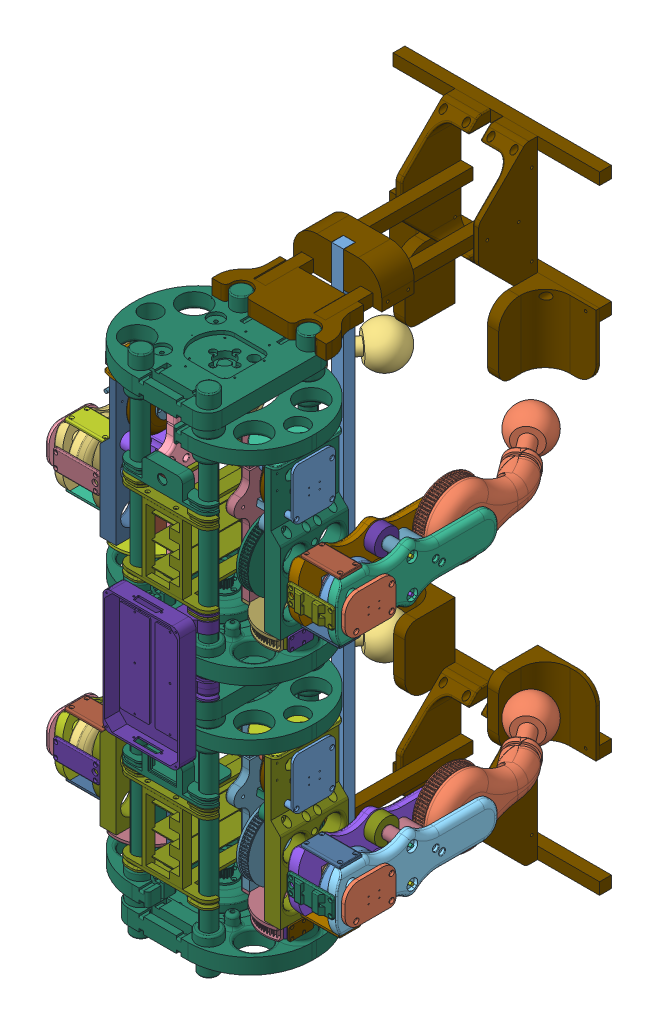
SolidWorks assembly openDogv2_12, configuration Default. Lengths in mm.
Overall size (507.74 1062 621.38).
170 component instances, 145 part files, 0 mates.
Components (placement in the parent):
- openDogv2_12.stp-1: openDogv2_12.stp [Default] at origin size (507.74 1062 621.38)
  - leg (1).stp-1: leg (1).stp [Default] at (0 150 0) size (214.22 298 498.86)
    - UpperLeg.stp-1: UpperLeg.stp [Default] at (-4.6931 5.6325 6.5458) size (199.22 129.38 296.86)
      - motor9225 v5 (2).stp-1: motor9225 v5 (2).stp [Default] at (-4 -156.5615 -13.5322) x (1 0 0) z (0 0.866025 0.5) size (39 92 92)
      - AMS.stp-1: AMS.stp [Default] at (-75 -241.6619 77.1108) x (1 0 0) z (0 0.707107 0.707107) size (28.8 88.43 93.61)
      - UpperLeg-0.stp-1: UpperLeg-0.stp [Default] at origin size (19 40 40)
      - UpperLeg-1.stp-1: UpperLeg-1.stp [Default] at origin size (119.92 20 20)
      - UpperLeg-2.stp-1: UpperLeg-2.stp [Default] at origin size (17.12 104.6 278)
      - UpperLeg-3.stp-1: UpperLeg-3.stp [Default] at origin size (82.92 5.08 5.08)
      - UpperLeg-4.stp-1: UpperLeg-4.stp [Default] at origin size (82.92 5.08 5.08)
      - UpperLeg-5.stp-1: UpperLeg-5.stp [Default] at origin size (20.04 104.6 278)
      - UpperLeg-6.stp-1: UpperLeg-6.stp [Default] at origin size (64.92 5.17 37.57)
      - UpperLeg-7.stp-1: UpperLeg-7.stp [Default] at origin size (66.92 5.17 37.57)
      - UpperLeg-8.stp-1: UpperLeg-8.stp [Default] at origin size (4 37 37)
      - UpperLeg-9.stp-1: UpperLeg-9.stp [Default] at origin size (4 37 37)
      - UpperLeg-10.stp-1: UpperLeg-10.stp [Default] at origin size (50 76 69.55)
      - UpperLeg-11.stp-1: UpperLeg-11.stp [Default] at origin size (55 114 114)
      - UpperLeg-12.stp-1: UpperLeg-12.stp [Default] at origin size (78.92 34.88 10)
      - UpperLeg-13.stp-1: UpperLeg-13.stp [Default] at origin size (18 42 42)
      - UpperLeg-14.stp-1: UpperLeg-14.stp [Default] at origin size (18 42 42)
    - Hip.stp-1: Hip.stp [Default] at (-8.6931 5.6325 6.5458) size (117.23 298 120)
      - motor9225 v5 (1).stp-1: motor9225 v5 (1).stp [Default] at (0 -150 0) size (39 92 92)
      - AMS v2.stp-1: AMS v2.stp [Default] at (-30.7 -40.5 -1.0837) x (0 0 1) z (-1 0 0) size (72 88 26.8)
      - Hip-15.stp-1: Hip-15.stp [Default] at origin size (25 40 40)
      - Hip-16.stp-1: Hip-16.stp [Default] at origin size (4 37 37)
      - Hip-17.stp-1: Hip-17.stp [Default] at origin size (15 34 34)
      - Hip-18.stp-1: Hip-18.stp [Default] at origin size (6 19 19)
      - Hip-19.stp-1: Hip-19.stp [Default] at origin size (37.9 6 6)
      - Hip-20.stp-1: Hip-20.stp [Default] at origin size (90.92 17.5 120)
      - Hip-21.stp-1: Hip-21.stp [Default] at origin size (37 4 37)
      - Hip-22.stp-1: Hip-22.stp [Default] at origin size (37 4 37)
      - Hip-23.stp-1: Hip-23.stp [Default] at origin size (4 37 37)
      - Hip-24.stp-1: Hip-24.stp [Default] at origin size (11 34 34)
      - Hip-25.stp-1: Hip-25.stp [Default] at origin size (4 37 37)
      - Hip-26.stp-1: Hip-26.stp [Default] at origin size (91.54 36 120)
      - Hip-27.stp-1: Hip-27.stp [Default] at origin size (31 244.5 108.11)
      - Hip-28.stp-1: Hip-28.stp [Default] at origin size (55 61.11 102.11)
      - Hip-29.stp-1: Hip-29.stp [Default] at origin size (27.22 244.5 115)
      - Hip-30.stp-1: Hip-30.stp [Default] at origin size (5.5 23 90.9)
      - Hip-31.stp-1: Hip-31.stp [Default] at origin size (3 23 41.45)
      - Hip-32.stp-1: Hip-32.stp [Default] at origin size (3 23 41.45)
    - LowerLeg.stp-1: LowerLeg.stp [Default] at (-4.6931 5.6325 6.5458) size (142.86 114.11 287.97)
  - leg (1)(Mirror).stp-1: leg (1)(Mirror).stp [Default] at (-371.132 150 0) x (-1 0 0) z (0 0 -1) size (214.22 297.5 498.86)
    - UpperLeg(Mirror).stp-1: UpperLeg(Mirror).stp [Default] at (12.6931 5.6325 -6.5458) size (199.22 129.38 296.86)
      - motor9225 v5 (2)(Mirror).stp-1: motor9225 v5 (2)(Mirror).stp [Default] at (-4 -156.5615 13.5322) x (1 0 0) z (0 -0.866025 0.5) size (39 92 92)
      - AMS(Mirror).stp-1: AMS(Mirror).stp [Default] at (-75 -241.6619 -77.1108) x (1 0 0) z (0 -0.707107 0.707107) size (28.8 88.43 93.61)
      - UpperLeg(Mirror)-33.stp-1: UpperLeg(Mirror)-33.stp [Default] at origin size (19 40 40)
      - UpperLeg(Mirror)-34.stp-1: UpperLeg(Mirror)-34.stp [Default] at origin size (119.92 20 20)
      - UpperLeg(Mirror)-35.stp-1: UpperLeg(Mirror)-35.stp [Default] at origin size (17.12 104.6 278)
      - UpperLeg(Mirror)-36.stp-1: UpperLeg(Mirror)-36.stp [Default] at origin size (82.92 5.08 5.08)
      - UpperLeg(Mirror)-37.stp-1: UpperLeg(Mirror)-37.stp [Default] at origin size (82.92 5.08 5.08)
      - UpperLeg(Mirror)-38.stp-1: UpperLeg(Mirror)-38.stp [Default] at origin size (64.92 5.12 37.57)
      - UpperLeg(Mirror)-39.stp-1: UpperLeg(Mirror)-39.stp [Default] at origin size (66.92 5.01 37.57)
      - UpperLeg(Mirror)-40.stp-1: UpperLeg(Mirror)-40.stp [Default] at origin size (4 37 37)
      - UpperLeg(Mirror)-41.stp-1: UpperLeg(Mirror)-41.stp [Default] at origin size (4 37 37)
      - UpperLeg(Mirror)-42.stp-1: UpperLeg(Mirror)-42.stp [Default] at origin size (50 76 69.55)
      - UpperLeg(Mirror)-43.stp-1: UpperLeg(Mirror)-43.stp [Default] at origin size (55 114 114)
      - UpperLeg(Mirror)-44.stp-1: UpperLeg(Mirror)-44.stp [Default] at origin size (20.04 104.6 278)
      - UpperLeg(Mirror)-45.stp-1: UpperLeg(Mirror)-45.stp [Default] at origin size (78.92 34.88 4.01)
    - Hip(Mirror).stp-1: Hip(Mirror).stp [Default] at (8.6931 5.6325 -6.5458) size (117.23 297.5 120)
      - motor9225 v5 (1)(Mirror).stp-1: motor9225 v5 (1)(Mirror).stp [Default] at (0 -150 0) size (39 92 92)
      - AMS v2(Mirror).stp-1: AMS v2(Mirror).stp [Default] at (-30.7 -40.5 1.0837) x (0 0 -1) z (1 0 0) size (72 88 26.8)
      - Hip(Mirror)-46.stp-1: Hip(Mirror)-46.stp [Default] at origin size (25 40 40)
      - Hip(Mirror)-47.stp-1: Hip(Mirror)-47.stp [Default] at origin size (4 37 37)
      - Hip(Mirror)-48.stp-1: Hip(Mirror)-48.stp [Default] at origin size (15 34 34)
      - Hip(Mirror)-49.stp-1: Hip(Mirror)-49.stp [Default] at origin size (6 19 19)
      - Hip(Mirror)-50.stp-1: Hip(Mirror)-50.stp [Default] at origin size (37.9 6 6)
      - Hip(Mirror)-51.stp-1: Hip(Mirror)-51.stp [Default] at origin size (4 37 37)
      - Hip(Mirror)-52.stp-1: Hip(Mirror)-52.stp [Default] at origin size (11 34 34)
      - Hip(Mirror)-53.stp-1: Hip(Mirror)-53.stp [Default] at origin size (4 37 37)
      - Hip(Mirror)-54.stp-1: Hip(Mirror)-54.stp [Default] at origin size (31 244.5 108.11)
      - Hip(Mirror)-55.stp-1: Hip(Mirror)-55.stp [Default] at origin size (37 4 37)
      - Hip(Mirror)-56.stp-1: Hip(Mirror)-56.stp [Default] at origin size (37 4 37)
      - Hip(Mirror)-57.stp-1: Hip(Mirror)-57.stp [Default] at origin size (90.92 17.5 120)
      - Hip(Mirror)-58.stp-1: Hip(Mirror)-58.stp [Default] at origin size (55 61.11 102.11)
      - Hip(Mirror)-59.stp-1: Hip(Mirror)-59.stp [Default] at origin size (91.54 36 120)
      - Hip(Mirror)-60.stp-1: Hip(Mirror)-60.stp [Default] at origin size (27.22 244.5 115)
      - Hip(Mirror)-61.stp-1: Hip(Mirror)-61.stp [Default] at origin size (3 23 41.45)
      - Hip(Mirror)-62.stp-1: Hip(Mirror)-62.stp [Default] at origin size (5.5 23 90.9)
      - Hip(Mirror)-63.stp-1: Hip(Mirror)-63.stp [Default] at origin size (3 23 41.45)
      - Hip(Mirror)-64.stp-1: Hip(Mirror)-64.stp [Default] at origin size (8.19 37 24)
    - LowerLeg(Mirror).stp-1: LowerLeg(Mirror).stp [Default] at (12.6931 5.6325 -6.5458) size (142.86 114.11 287.97)
  - leg (1)_1.stp-1: leg (1)_1.stp [Default] at (0 575 0) size (214.22 298 498.86)
    - UpperLeg_1.stp-1: UpperLeg_1.stp [Default] at (-4.6931 5.6325 6.5458) size (199.22 129.38 296.86)
      - motor9225 v5 (2).stp-1: motor9225 v5 (2).stp [Default] at (-4 -156.5615 -13.5322) x (1 0 0) z (0 0.866025 0.5) size (39 92 92)
      - AMS.stp-1: AMS.stp [Default] at (-75 -241.6619 77.1108) x (1 0 0) z (0 0.707107 0.707107) size (28.8 88.43 93.61)
      - UpperLeg_1-65.stp-1: UpperLeg_1-65.stp [Default] at origin size (19 40 40)
      - UpperLeg_1-66.stp-1: UpperLeg_1-66.stp [Default] at origin size (119.92 20 20)
      - UpperLeg_1-67.stp-1: UpperLeg_1-67.stp [Default] at origin size (17.12 104.6 278)
      - UpperLeg_1-68.stp-1: UpperLeg_1-68.stp [Default] at origin size (82.92 5.08 5.08)
      - UpperLeg_1-69.stp-1: UpperLeg_1-69.stp [Default] at origin size (82.92 5.08 5.08)
      - UpperLeg_1-70.stp-1: UpperLeg_1-70.stp [Default] at origin size (20.04 104.6 278)
      - UpperLeg_1-71.stp-1: UpperLeg_1-71.stp [Default] at origin size (64.92 5.17 37.57)
      - UpperLeg_1-72.stp-1: UpperLeg_1-72.stp [Default] at origin size (66.92 5.17 37.57)
      - UpperLeg_1-73.stp-1: UpperLeg_1-73.stp [Default] at origin size (4 37 37)
      - UpperLeg_1-74.stp-1: UpperLeg_1-74.stp [Default] at origin size (4 37 37)
      - UpperLeg_1-75.stp-1: UpperLeg_1-75.stp [Default] at origin size (50 76 69.55)
      - UpperLeg_1-76.stp-1: UpperLeg_1-76.stp [Default] at origin size (55 114 114)
      - UpperLeg_1-77.stp-1: UpperLeg_1-77.stp [Default] at origin size (78.92 34.88 10)
      - UpperLeg_1-78.stp-1: UpperLeg_1-78.stp [Default] at origin size (18 42 42)
      - UpperLeg_1-79.stp-1: UpperLeg_1-79.stp [Default] at origin size (18 42 42)
    - Hip_1.stp-1: Hip_1.stp [Default] at (-8.6931 5.6325 6.5458) size (117.23 298 120)
      - motor9225 v5 (1).stp-1: motor9225 v5 (1).stp [Default] at (0 -150 0) size (39 92 92)
      - AMS v2.stp-1: AMS v2.stp [Default] at (-30.7 -40.5 -1.0837) x (0 0 1) z (-1 0 0) size (72 88 26.8)
      - Hip_1-80.stp-1: Hip_1-80.stp [Default] at origin size (25 40 40)
      - Hip_1-81.stp-1: Hip_1-81.stp [Default] at origin size (4 37 37)
      - Hip_1-82.stp-1: Hip_1-82.stp [Default] at origin size (15 34 34)
      - Hip_1-83.stp-1: Hip_1-83.stp [Default] at origin size (6 19 19)
      - Hip_1-84.stp-1: Hip_1-84.stp [Default] at origin size (37.9 6 6)
      - Hip_1-85.stp-1: Hip_1-85.stp [Default] at origin size (90.92 17.5 120)
      - Hip_1-86.stp-1: Hip_1-86.stp [Default] at origin size (37 4 37)
      - Hip_1-87.stp-1: Hip_1-87.stp [Default] at origin size (37 4 37)
      - Hip_1-88.stp-1: Hip_1-88.stp [Default] at origin size (4 37 37)
      - Hip_1-89.stp-1: Hip_1-89.stp [Default] at origin size (11 34 34)
      - Hip_1-90.stp-1: Hip_1-90.stp [Default] at origin size (4 37 37)
      - Hip_1-91.stp-1: Hip_1-91.stp [Default] at origin size (91.54 36 120)
      - Hip_1-92.stp-1: Hip_1-92.stp [Default] at origin size (31 244.5 108.11)
      - Hip_1-93.stp-1: Hip_1-93.stp [Default] at origin size (55 61.11 102.11)
      - Hip_1-94.stp-1: Hip_1-94.stp [Default] at origin size (27.22 244.5 115)
      - Hip_1-95.stp-1: Hip_1-95.stp [Default] at origin size (5.5 23 90.9)
      - Hip_1-96.stp-1: Hip_1-96.stp [Default] at origin size (3 23 41.45)
      - Hip_1-97.stp-1: Hip_1-97.stp [Default] at origin size (3 23 41.45)
    - LowerLeg.stp-1: LowerLeg.stp [Default] at (-4.6931 5.6325 6.5458) size (142.86 114.11 287.97)
  - leg (1)(Mirror)_1.stp-1: leg (1)(Mirror)_1.stp [Default] at (-371.132 575 0) x (-1 0 0) z (0 0 -1) size (214.22 297.5 498.86)
    - UpperLeg(Mirror)_1.stp-1: UpperLeg(Mirror)_1.stp [Default] at (12.6931 5.6325 -6.5458) size (199.22 129.38 296.86)
      - motor9225 v5 (2)(Mirror).stp-1: motor9225 v5 (2)(Mirror).stp [Default] at (-4 -156.5615 13.5322) x (1 0 0) z (0 -0.866025 0.5) size (39 92 92)
      - AMS(Mirror).stp-1: AMS(Mirror).stp [Default] at (-75 -241.6619 -77.1108) x (1 0 0) z (0 -0.707107 0.707107) size (28.8 88.43 93.61)
      - UpperLeg(Mirror)_1-98.stp-1: UpperLeg(Mirror)_1-98.stp [Default] at origin size (19 40 40)
      - UpperLeg(Mirror)_1-99.stp-1: UpperLeg(Mirror)_1-99.stp [Default] at origin size (119.92 20 20)
      - UpperLeg(Mirror)_1-100.stp-1: UpperLeg(Mirror)_1-100.stp [Default] at origin size (17.12 104.6 278)
      - UpperLeg(Mirror)_1-101.stp-1: UpperLeg(Mirror)_1-101.stp [Default] at origin size (82.92 5.08 5.08)
      - UpperLeg(Mirror)_1-102.stp-1: UpperLeg(Mirror)_1-102.stp [Default] at origin size (82.92 5.08 5.08)
      - UpperLeg(Mirror)_1-103.stp-1: UpperLeg(Mirror)_1-103.stp [Default] at origin size (64.92 5.12 37.57)
      - UpperLeg(Mirror)_1-104.stp-1: UpperLeg(Mirror)_1-104.stp [Default] at origin size (66.92 5.01 37.57)
      - UpperLeg(Mirror)_1-105.stp-1: UpperLeg(Mirror)_1-105.stp [Default] at origin size (4 37 37)
      - UpperLeg(Mirror)_1-106.stp-1: UpperLeg(Mirror)_1-106.stp [Default] at origin size (4 37 37)
      - UpperLeg(Mirror)_1-107.stp-1: UpperLeg(Mirror)_1-107.stp [Default] at origin size (50 76 69.55)
      - UpperLeg(Mirror)_1-108.stp-1: UpperLeg(Mirror)_1-108.stp [Default] at origin size (55 114 114)
      - UpperLeg(Mirror)_1-109.stp-1: UpperLeg(Mirror)_1-109.stp [Default] at origin size (20.04 104.6 278)
      - UpperLeg(Mirror)_1-110.stp-1: UpperLeg(Mirror)_1-110.stp [Default] at origin size (78.92 34.88 4.01)
    - Hip(Mirror)_1.stp-1: Hip(Mirror)_1.stp [Default] at (8.6931 5.6325 -6.5458) size (117.23 297.5 120)
      - motor9225 v5 (1)(Mirror).stp-1: motor9225 v5 (1)(Mirror).stp [Default] at (0 -150 0) size (39 92 92)
      - AMS v2(Mirror).stp-1: AMS v2(Mirror).stp [Default] at (-30.7 -40.5 1.0837) x (0 0 -1) z (1 0 0) size (72 88 26.8)
      - Hip(Mirror)_1-111.stp-1: Hip(Mirror)_1-111.stp [Default] at origin size (25 40 40)
      - Hip(Mirror)_1-112.stp-1: Hip(Mirror)_1-112.stp [Default] at origin size (4 37 37)
      - Hip(Mirror)_1-113.stp-1: Hip(Mirror)_1-113.stp [Default] at origin size (15 34 34)
      - Hip(Mirror)_1-114.stp-1: Hip(Mirror)_1-114.stp [Default] at origin size (6 19 19)
      - Hip(Mirror)_1-115.stp-1: Hip(Mirror)_1-115.stp [Default] at origin size (37.9 6 6)
      - Hip(Mirror)_1-116.stp-1: Hip(Mirror)_1-116.stp [Default] at origin size (4 37 37)
      - Hip(Mirror)_1-117.stp-1: Hip(Mirror)_1-117.stp [Default] at origin size (11 34 34)
      - Hip(Mirror)_1-118.stp-1: Hip(Mirror)_1-118.stp [Default] at origin size (4 37 37)
      - Hip(Mirror)_1-119.stp-1: Hip(Mirror)_1-119.stp [Default] at origin size (31 244.5 108.11)
      - Hip(Mirror)_1-120.stp-1: Hip(Mirror)_1-120.stp [Default] at origin size (37 4 37)
      - Hip(Mirror)_1-121.stp-1: Hip(Mirror)_1-121.stp [Default] at origin size (37 4 37)
      - Hip(Mirror)_1-122.stp-1: Hip(Mirror)_1-122.stp [Default] at origin size (90.92 17.5 120)
      - Hip(Mirror)_1-123.stp-1: Hip(Mirror)_1-123.stp [Default] at origin size (55 61.11 102.11)
      - Hip(Mirror)_1-124.stp-1: Hip(Mirror)_1-124.stp [Default] at origin size (91.54 36 120)
      - Hip(Mirror)_1-125.stp-1: Hip(Mirror)_1-125.stp [Default] at origin size (27.22 244.5 115)
      - Hip(Mirror)_1-126.stp-1: Hip(Mirror)_1-126.stp [Default] at origin size (3 23 41.45)
      - Hip(Mirror)_1-127.stp-1: Hip(Mirror)_1-127.stp [Default] at origin size (5.5 23 90.9)
      - Hip(Mirror)_1-128.stp-1: Hip(Mirror)_1-128.stp [Default] at origin size (3 23 41.45)
      - Hip(Mirror)_1-129.stp-1: Hip(Mirror)_1-129.stp [Default] at origin size (8.19 37 24)
    - LowerLeg(Mirror).stp-1: LowerLeg(Mirror).stp [Default] at (12.6931 5.6325 -6.5458) size (142.86 114.11 287.97)
  - Body.stp-1: Body.stp [Default] at (-8.6931 5.6325 7.3263) size (313.03 858 217.83)
  - Odrives v7.stp-1: Odrives v7.stp [Default] at (-201.75 36 30) size (155 147.8 161)
  - Odrives v7.stp-2: Odrives v7.stp [Default] at (-201.75 461 30) size (155 147.8 161)
  - electronics.stp-1: electronics.stp [Default] at origin size (155 219.93 55.63)
  - stand.stp-1: stand.stp [Default] at origin size (350 1001.75 404.6)
  - stand.stp-2: stand.stp [Default] at (-386.9004 510.2224 0) x (-1 0 0) z (0 0 1) size (350 1001.75 404.6)
  - openDogv2_12.stp-1: openDogv2_12.stp [Default] at origin size (20 941.5 20)
